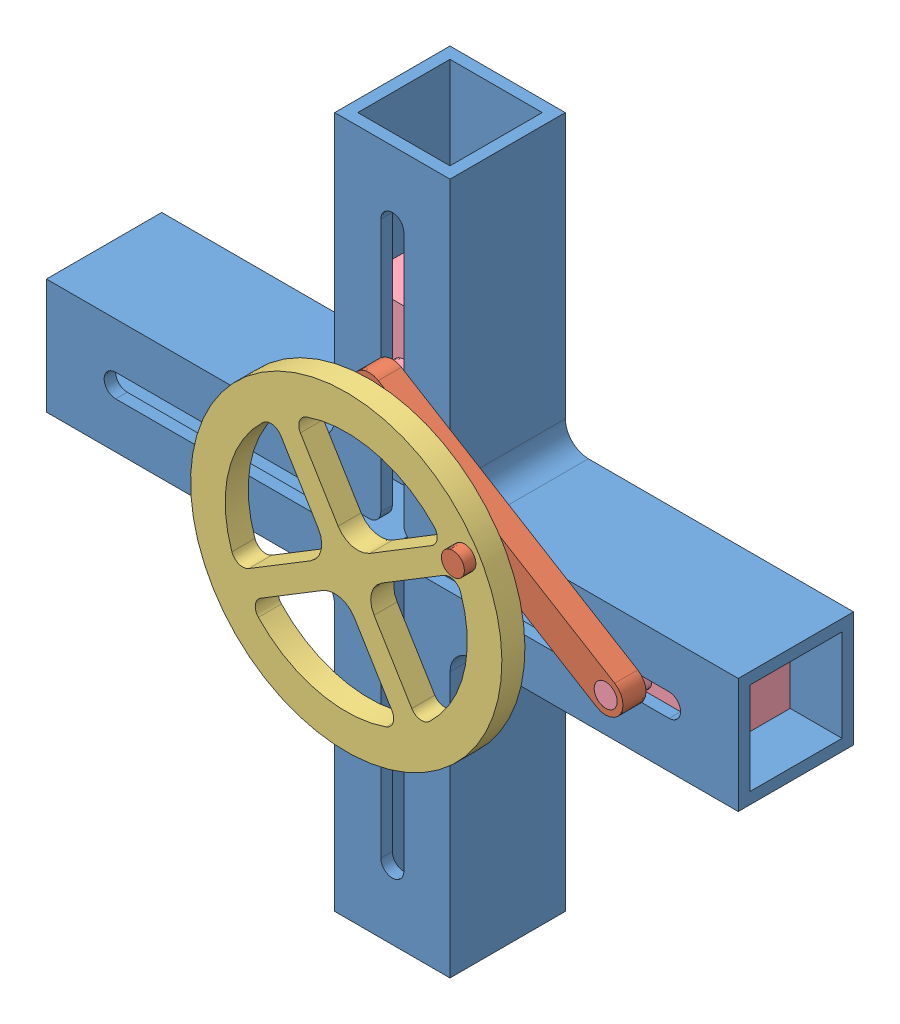
SolidWorks assembly Elliptrical Trammel Assembly, configuration Default. Lengths in mm.
Overall size (120 120 30).
5 component instances, 4 part files, 11 mates.
Components (placement in the parent):
- Body-1: Body [Default] at (33.7582 68.528 93.921) size (120 120 20)
- Connecting Rod-1: Connecting Rod [Default] at (54.2599 81.0051 103.921) x (-0.85424 0.519879 0) z (0 0 1) size (54 6 10)
- Crank-1: Crank [Default] at (33.7582 68.528 107.921) x (0.85424 0.519879 0) z (0 0 1) size (54 54 4)
- Piston1-1: Piston1 [Default] at (33.7582 103.4822 93.921) x (0 0 -1) z (0 -1 0) size (22 16 20)
- Piston1-2: Piston1 [Default] at (64.7617 68.528 93.921) x (0 0 -1) z (1 0 0) size (22 16 20)
Mates (geometry in assembly coordinates):
- Parallel1: parallel anti-aligned: plane of Piston1-1 through (41.7582 83.4822 85.921) normal (0 0 -1); plane of Body-1 through (25.7582 -14.0994 85.921) normal (0 0 1)
- Coincident6: coincident anti-aligned: plane of Body-1 through (25.7582 -14.0994 85.921) normal (0 0 1); plane of Piston1-1 through (41.7582 83.4822 85.921) normal (0 0 -1)
- Coincident7: coincident anti-aligned: plane of Body-1 through (41.7582 -14.0994 101.921) normal (-1 0 0); plane of Piston1-1 through (41.7582 83.4822 101.921) normal (1 0 0)
- Coincident8: coincident anti-aligned: plane of Body-1 through (25.7582 -14.0994 85.921) normal (0 0 1); plane of Piston1-2 through (84.7617 76.528 85.921) normal (0 0 -1)
- Coincident9: coincident anti-aligned: plane of Body-1 through (-48.8692 76.528 85.921) normal (0 -1 0); plane of Piston1-2 through (84.7617 76.528 101.921) normal (0 1 0)
- Coincident11: coincident anti-aligned: plane of Body-1 through (19.7582 54.528 103.921) normal (0 0 1); plane of Connecting Rod-1 through (74.7617 68.528 103.921) normal (0 0 -1)
- Concentric1: concentric aligned: cylinder of Connecting Rod-1 through (74.7617 68.528 107.921) axis (0 0 -1) radius 2; cylinder of Piston1-2 through (74.7617 68.528 107.921) axis (0 0 -1) radius 2
- Concentric2: concentric aligned: cylinder of Connecting Rod-1 through (33.7582 93.4822 107.921) axis (0 0 -1) radius 2; cylinder of Piston1-1 through (33.7582 93.4822 107.921) axis (0 0 -1) radius 2
- Coincident12: coincident anti-aligned: plane of Connecting Rod-1 through (74.7617 68.528 107.921) normal (0 0 1); plane of Crank-1 through (33.7582 68.528 107.921) normal (0 0 -1)
- Concentric3: concentric aligned: cylinder of Connecting Rod-1 through (54.2599 81.0051 113.921) axis (0 0 -1) radius 2; cylinder of Crank-1 through (54.2599 81.0051 111.921) axis (0 0 -1) radius 2
- Concentric4: concentric aligned: circle of Crank-1; circle of assembly
